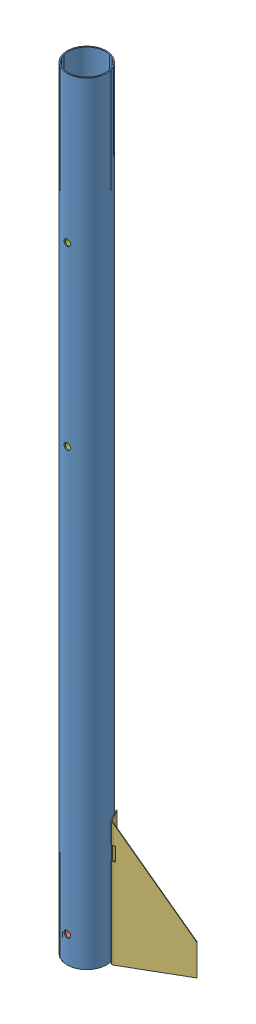
SolidWorks assembly rocket, configuration Default. Lengths in mm.
Overall size (97.97 500 47.6).
304 component instances, 53 part files, 30 mates.
Components (placement in the parent):
- pipe-1: pipe [Default] at (110.8047 11.7037 420.9903) size (25.5 500 25.5)
- nozle-2: nozle [Default] at (113.2966 34.1262 426.4615) x (0 -1 0) z (-0.414497 0 -0.91005) size (27 24 24)
- stabiliser-1: stabiliser [Default] at (90.1864 51.7037 433.7403) x (-1 0 0) z (0 -1 0) size (10 40.92 80) (hidden)
- pan head cross collar screw_din-2: pan head cross collar screw_din [DIN 967 - M4 x 5 - Z --- 3.6C] at (110.8047 29.0148 437.2903) x (0 0 -1) z (-0.790424 0.61256 0) size (7.93 10 10) (hidden)
- stabiliser-2: stabiliser [Default] at (132.1556 51.7037 432.4712) x (0.5 0 0.866025) z (0 -1 0) size (10 40.92 80)
- stabiliser-3: stabiliser [Default] at (110.072 51.7037 396.7593) x (0.5 0 -0.866025) z (0 -1 0) size (10 40.92 80)
- pan head cross collar screw_din-5: pan head cross collar screw_din [DIN 967 - M4 x 5 - Z --- 3.6C] at (124.9209 29.0148 412.8403) x (-0.866025 0 0.5) z (0.395212 0.61256 0.684527) size (7.93 10 10)
- pan head cross collar screw_din-6: pan head cross collar screw_din [DIN 967 - M4 x 5 - Z --- 3.6C] at (96.6885 29.0148 412.8403) x (0.866025 0 0.5) z (0.395212 0.61256 -0.684527) size (7.93 10 10)
- fuel with shielding and channel-1: fuel with shielding and channel [Default] at (110.8047 38.7037 420.9903) x (-0.053752 0 -0.998554) z (0.998554 0 -0.053752) size (24 85 24)
  - fuel-1: fuel [Default] at origin size (22 85 22)
  - fuel shielding-1: fuel shielding [Default] at origin size (24 85 24)
- fuel with shielding and channel-2: fuel with shielding and channel [Default] at (110.8047 123.7037 420.9903) x (-0.053752 0 -0.998554) z (0.998554 0 -0.053752) size (24 85 24)
  - fuel-1: fuel [Default] at origin size (22 85 22)
  - fuel shielding-1: fuel shielding [Default] at origin size (24 85 24)
- fuel with shielding-1: fuel with shielding [Default] at (110.8047 208.7037 420.9903) size (24 85 24)
  - fuel-1: fuel [Default] at origin size (22 85 22)
  - fuel shielding-1: fuel shielding [Default] at origin size (24 85 24)
- cap-1: cap [Default] at (112.1429 290.3844 427.2426) x (0 -1 0) z (0.209294 0 0.977853) size (18 24 24)
- o ring-3: o ring [Default] at (110.8047 24.4537 420.9903) size (24 1.5 24)
- o ring-4: o ring [Default] at (110.8047 33.9537 420.9903) size (24 1.5 24)
- o ring-5: o ring [Default] at (110.8047 24.4537 420.9903) size (24 1.5 24)
- o ring-7: o ring [Default] at (110.8047 307.4537 420.9903) x (0.994876 0 -0.101103) z (0.101103 0 0.994876) size (24 1.5 24)
- o ring-8: o ring [Default] at (110.8047 297.9537 420.9903) x (0.994876 0 -0.101103) z (0.101103 0 0.994876) size (24 1.5 24)
- electronics module-1: electronics module [Default] at (184.9767 308.3029 400.1739) x (0 0 1) z (-1 0 0) size (21.83 94.3 23.62)
  - PCB-1: PCB [Default] at (20.7064 167.5504 -10.283) x (0 -1 0) z (-1 0 0) size (88.26 23.62 14)
    - R05-1: R05 [Default] at origin size (0.95 1.7 0.6)
      - 959206216-1: 959206216 [Default] at (123.9521 73.9609 0) size (0.95 0.27 0.6)
        - Extruded-1: Extruded [Default] at origin size (0.95 0.27 0.6)
      - 959206352-1: 959206352 [Default] at (123.9521 74.6759 0) size (0.95 1.16 0.6)
        - Extruded-1-1: Extruded-1 [Default] at origin size (0.95 1.16 0.6)
      - 959206216-2: 959206216 [Default] at (123.9521 75.3909 0) size (0.95 0.27 0.6)
        - Extruded-1: Extruded [Default] at origin size (0.95 0.27 0.6)
    - R04-1: R04 [Default] at origin size (0.95 1.7 0.6)
      - 959206216-1: 959206216 [Default] at (141.478 81.581 0) size (0.95 0.27 0.6)
        - Extruded-1: Extruded [Default] at origin size (0.95 0.27 0.6)
      - 959206352-1: 959206352 [Default] at (141.478 82.296 0) size (0.95 1.16 0.6)
        - Extruded-1-1: Extruded-1 [Default] at origin size (0.95 1.16 0.6)
      - 959206216-2: 959206216 [Default] at (141.478 83.011 0) size (0.95 0.27 0.6)
        - Extruded-1: Extruded [Default] at origin size (0.95 0.27 0.6)
    - R03-1: R03 [Default] at origin size (3.35 1.75 0.75)
      - 959206760-1: 959206760 [Default] at (147.8506 77.6516 0) size (0.49 1.75 0.75)
        - Extruded-2-1: Extruded-2 [Default] at origin size (0.49 1.75 0.75)
      - 959206896-1: 959206896 [Default] at (149.2781 77.6516 0) size (2.36 1.75 0.75)
        - Extruded-3-1: Extruded-3 [Default] at origin size (2.36 1.75 0.75)
      - 959206760-2: 959206760 [Default] at (150.7056 77.6516 0) size (0.49 1.75 0.75)
        - Extruded-2-1: Extruded-2 [Default] at origin size (0.49 1.75 0.75)
    - R02-1: R02 [Default] at origin size (1.75 3.35 0.75)
      - 959207032-1: 959207032 [Default] at (128.1431 81.3844 0) size (1.75 0.49 0.75)
        - Extruded-4-1: Extruded-4 [Default] at origin size (1.75 0.49 0.75)
      - 959207168-1: 959207168 [Default] at (128.1431 79.9569 0) size (1.75 2.36 0.75)
        - Extruded-5-1: Extruded-5 [Default] at origin size (1.75 2.36 0.75)
      - 959207032-2: 959207032 [Default] at (128.1431 78.5294 0) size (1.75 0.49 0.75)
        - Extruded-4-1: Extruded-4 [Default] at origin size (1.75 0.49 0.75)
    - R01-1: R01 [Default] at origin size (3.35 1.75 0.75)
      - 959206760-1: 959206760 [Default] at (117.3285 91.9479 0) size (0.49 1.75 0.75)
        - Extruded-2-1: Extruded-2 [Default] at origin size (0.49 1.75 0.75)
      - 959206896-1: 959206896 [Default] at (115.901 91.9479 0) size (2.36 1.75 0.75)
        - Extruded-3-1: Extruded-3 [Default] at origin size (2.36 1.75 0.75)
      - 959206760-2: 959206760 [Default] at (114.4735 91.9479 0) size (0.49 1.75 0.75)
        - Extruded-2-1: Extruded-2 [Default] at origin size (0.49 1.75 0.75)
    - U3-1: U3 [Default] at origin size (43.25 15.95 5.5)
      - 959206080-1: 959206080 [Default] at (102.177 84.441 -2.3912) size (43.25 15.95 2)
        - Extruded-6-1: Extruded-6 [Default] at origin size (43.25 15.95 2)
      - 959205944-1: 959205944 [Default] at (85.217 88.291 -2.8912) size (0.4 0.4 5.5)
        - Extruded-7-1: Extruded-7 [Default] at origin size (0.4 0.4 5.5)
      - 959205944-2: 959205944 [Default] at (85.217 85.751 -2.8912) size (0.4 0.4 5.5)
        - Extruded-7-1: Extruded-7 [Default] at origin size (0.4 0.4 5.5)
      - 959205944-3: 959205944 [Default] at (82.677 88.291 -2.8912) size (0.4 0.4 5.5)
        - Extruded-7-1: Extruded-7 [Default] at origin size (0.4 0.4 5.5)
      - 959205944-4: 959205944 [Default] at (82.677 85.751 -2.8912) size (0.4 0.4 5.5)
        - Extruded-7-1: Extruded-7 [Default] at origin size (0.4 0.4 5.5)
      - 959205944-5: 959205944 [Default] at (85.217 83.211 -2.8912) size (0.4 0.4 5.5)
        - Extruded-7-1: Extruded-7 [Default] at origin size (0.4 0.4 5.5)
      - 959205944-6: 959205944 [Default] at (85.217 80.671 -2.8912) size (0.4 0.4 5.5)
        - Extruded-7-1: Extruded-7 [Default] at origin size (0.4 0.4 5.5)
      - 959205944-7: 959205944 [Default] at (82.677 83.211 -2.8912) size (0.4 0.4 5.5)
        - Extruded-7-1: Extruded-7 [Default] at origin size (0.4 0.4 5.5)
      - 959205944-8: 959205944 [Default] at (82.677 80.671 -2.8912) size (0.4 0.4 5.5)
        - Extruded-7-1: Extruded-7 [Default] at origin size (0.4 0.4 5.5)
    - R11-1: R11 [Default] at origin size (1.35 2.2 0.7)
      - 959207304-1: 959207304 [Default] at (133.9849 94.0691 0) size (1.35 0.42 0.7)
        - Extruded-8-1: Extruded-8 [Default] at origin size (1.35 0.42 0.7)
      - 959207440-1: 959207440 [Default] at (133.9849 93.1791 0) size (1.35 1.36 0.7)
        - Extruded-9-1: Extruded-9 [Default] at origin size (1.35 1.36 0.7)
      - 959207304-2: 959207304 [Default] at (133.9849 92.2891 0) size (1.35 0.42 0.7)
        - Extruded-8-1: Extruded-8 [Default] at origin size (1.35 0.42 0.7)
    - Q3-1: Q3 [Default] at origin size (1.4 3 1)
      - 959206624-1: 959206624 [Default] at (105.664 90.805 0.1) size (1.4 3 1)
        - Extruded-10-1: Extruded-10 [Default] at origin size (1.4 3 1)
    - P6-1: P6 [Default] at origin size (16.31 15.21 2.47)
      - User Library-Micro SD-1: User Library-Micro SD [Default] at (103.6713 76.9862 0.04) x (-1 0 0) z (0 0 1) size (16.31 15.21 2.47)
    - Q1-1: Q1 [Default] at origin size (3 1.4 1)
      - 959206488-1: 959206488 [Default] at (75.057 92.3634 0.1) size (3 1.4 1)
        - Extruded-11-1: Extruded-11 [Default] at origin size (3 1.4 1)
    - C1-1: C1 [Default] at origin size (3.4 1.8 1.9)
      - 959208392-1: 959208392 [Default] at (133.022 83.687 0) size (0.5 1.8 1.9)
        - Extruded-12-1: Extruded-12 [Default] at origin size (0.5 1.8 1.9)
      - 959208392-2: 959208392 [Default] at (130.122 83.687 0) size (0.5 1.8 1.9)
        - Extruded-12-1: Extruded-12 [Default] at origin size (0.5 1.8 1.9)
      - 959208256-1: 959208256 [Default] at (131.572 83.687 0) size (2.4 1.8 1.9)
        - Extruded-13-1: Extruded-13 [Default] at origin size (2.4 1.8 1.9)
    - C2-1: C2 [Default] at origin size (0.95 1.75 1)
      - 959208664-1: 959208664 [Default] at (140.8925 85.698 0) size (0.95 0.35 1)
        - Extruded-14-1: Extruded-14 [Default] at origin size (0.95 0.35 1)
      - 959208664-2: 959208664 [Default] at (140.8925 87.098 0) size (0.95 0.35 1)
        - Extruded-14-1: Extruded-14 [Default] at origin size (0.95 0.35 1)
      - 959208528-1: 959208528 [Default] at (140.8925 86.398 0) size (0.95 1.05 1)
        - Extruded-15-1: Extruded-15 [Default] at origin size (0.95 1.05 1)
    - C3-1: C3 [Default] at origin size (0.95 1.75 1)
      - 959208664-1: 959208664 [Default] at (146.558 83.0961 0) size (0.95 0.35 1)
        - Extruded-14-1: Extruded-14 [Default] at origin size (0.95 0.35 1)
      - 959208664-2: 959208664 [Default] at (146.558 84.4961 0) size (0.95 0.35 1)
        - Extruded-14-1: Extruded-14 [Default] at origin size (0.95 0.35 1)
      - 959208528-1: 959208528 [Default] at (146.558 83.7961 0) size (0.95 1.05 1)
        - Extruded-15-1: Extruded-15 [Default] at origin size (0.95 1.05 1)
    - C5-1: C5 [Default] at origin size (1.75 0.95 1)
      - 959208936-1: 959208936 [Default] at (142.772 80.518 0) size (0.35 0.95 1)
        - Extruded-16-1: Extruded-16 [Default] at origin size (0.35 0.95 1)
      - 959208936-2: 959208936 [Default] at (144.172 80.518 0) size (0.35 0.95 1)
        - Extruded-16-1: Extruded-16 [Default] at origin size (0.35 0.95 1)
      - 959208800-1: 959208800 [Default] at (143.472 80.518 0) size (1.05 0.95 1)
        - Extruded-17-1: Extruded-17 [Default] at origin size (1.05 0.95 1)
    - C6-1: C6 [Default] at origin size (1.75 0.95 1)
      - 959208800-1: 959208800 [Default] at (135.5285 81.379 0) size (1.05 0.95 1)
        - Extruded-17-1: Extruded-17 [Default] at origin size (1.05 0.95 1)
      - 959208936-1: 959208936 [Default] at (136.2285 81.379 0) size (0.35 0.95 1)
        - Extruded-16-1: Extruded-16 [Default] at origin size (0.35 0.95 1)
      - 959208936-2: 959208936 [Default] at (134.8286 81.379 0) size (0.35 0.95 1)
        - Extruded-16-1: Extruded-16 [Default] at origin size (0.35 0.95 1)
    - C7-1: C7 [Default] at origin size (0.95 1.75 1)
      - 959208528-1: 959208528 [Default] at (145.288 83.8282 0) size (0.95 1.05 1)
        - Extruded-15-1: Extruded-15 [Default] at origin size (0.95 1.05 1)
      - 959208664-1: 959208664 [Default] at (145.288 83.1282 0) size (0.95 0.35 1)
        - Extruded-14-1: Extruded-14 [Default] at origin size (0.95 0.35 1)
      - 959208664-2: 959208664 [Default] at (145.288 84.5282 0) size (0.95 0.35 1)
        - Extruded-14-1: Extruded-14 [Default] at origin size (0.95 0.35 1)
    - C8-1: C8 [Default] at origin size (1.45 2.2 1)
      - 959207984-1: 959207984 [Default] at (115.697 77.2073 0) size (1.45 1.2 1)
        - Extruded-18-1: Extruded-18 [Default] at origin size (1.45 1.2 1)
      - 959207848-1: 959207848 [Default] at (115.697 78.0573 0) size (1.45 0.5 1)
        - Extruded-19-1: Extruded-19 [Default] at origin size (1.45 0.5 1)
      - 959207848-2: 959207848 [Default] at (115.697 76.3573 0) size (1.45 0.5 1)
        - Extruded-19-1: Extruded-19 [Default] at origin size (1.45 0.5 1)
    - C9-1: C9 [Default] at origin size (0.95 1.75 1)
      - 959208528-1: 959208528 [Default] at (108.577 76.835 0) size (0.95 1.05 1)
        - Extruded-15-1: Extruded-15 [Default] at origin size (0.95 1.05 1)
      - 959208664-1: 959208664 [Default] at (108.577 76.135 0) size (0.95 0.35 1)
        - Extruded-14-1: Extruded-14 [Default] at origin size (0.95 0.35 1)
      - 959208664-2: 959208664 [Default] at (108.577 77.535 0) size (0.95 0.35 1)
        - Extruded-14-1: Extruded-14 [Default] at origin size (0.95 0.35 1)
    - C10-1: C10 [Default] at origin size (0.95 1.75 1)
      - 959208664-1: 959208664 [Default] at (109.7632 77.5843 0) size (0.95 0.35 1)
        - Extruded-14-1: Extruded-14 [Default] at origin size (0.95 0.35 1)
      - 959208664-2: 959208664 [Default] at (109.7632 76.1843 0) size (0.95 0.35 1)
        - Extruded-14-1: Extruded-14 [Default] at origin size (0.95 0.35 1)
      - 959208528-1: 959208528 [Default] at (109.7632 76.8843 0) size (0.95 1.05 1)
        - Extruded-15-1: Extruded-15 [Default] at origin size (0.95 1.05 1)
    - C11-1: C11 [Default] at origin size (0.95 1.75 1)
      - 959208664-1: 959208664 [Default] at (122.4827 75.652 0) size (0.95 0.35 1)
        - Extruded-14-1: Extruded-14 [Default] at origin size (0.95 0.35 1)
      - 959208664-2: 959208664 [Default] at (122.4827 77.052 0) size (0.95 0.35 1)
        - Extruded-14-1: Extruded-14 [Default] at origin size (0.95 0.35 1)
      - 959208528-1: 959208528 [Default] at (122.4827 76.352 0) size (0.95 1.05 1)
        - Extruded-15-1: Extruded-15 [Default] at origin size (0.95 1.05 1)
    - C12-1: C12 [Default] at origin size (1.75 0.95 1)
      - 959208936-1: 959208936 [Default] at (92.521 76.327 0) size (0.35 0.95 1)
        - Extruded-16-1: Extruded-16 [Default] at origin size (0.35 0.95 1)
      - 959208936-2: 959208936 [Default] at (91.121 76.327 0) size (0.35 0.95 1)
        - Extruded-16-1: Extruded-16 [Default] at origin size (0.35 0.95 1)
      - 959208800-1: 959208800 [Default] at (91.821 76.327 0) size (1.05 0.95 1)
        - Extruded-17-1: Extruded-17 [Default] at origin size (1.05 0.95 1)
    - P1-1: P1 [Default] at origin size (7.4 5.75 10.4)
      - P1-subassembly-1-1: P1-subassembly-1 [Default] at (131.5051 81.6569 -0.3912) x (-1 0 0) z (0 -1 0) size (7.4 10.4 5.75)
        - User Library-JST B2B-XH-A-1: User Library-JST B2B-XH-A [Default] at origin size (0.64 3.4 0.64)
        - User Library-JST B2B-XH-A-1-1: User Library-JST B2B-XH-A-1 [Default] at origin size (0.64 3.4 0.64)
        - User Library-JST B2B-XH-A-2-1: User Library-JST B2B-XH-A-2 [Default] at origin size (0.64 4.5 0.64)
        - User Library-JST B2B-XH-A-3-1: User Library-JST B2B-XH-A-3 [Default] at origin size (0.64 4.5 0.64)
        - User Library-JST B2B-XH-A-4-1: User Library-JST B2B-XH-A-4 [Default] at origin size (7.4 7 5.75)
    - P3-1: P3 [Default] at origin size (12.4 5.75 10.4)
      - SW3dPS-jst-b4b-xh-a-1-1: SW3dPS-jst-b4b-xh-a-1 [Default] at (134.0049 88.1301 -0.3912) x (-1 0 0) z (0 -1 0) size (12.4 10.4 5.75)
    - P4-1: P4 [Default] at origin
      - connector-1: connector [Default] at (76.2639 56.9549 -0.3912) x (0 1 0) z (0 0 -1)
    - P5-1: P5 [Default] at origin
      - connector-1: connector [Default] at (157.0351 111.9551 -0.3912) x (0 -1 0) z (0 0 -1)
    - Q2-1: Q2 [Default] at origin size (1.4 3 1)
      - 959206624-1: 959206624 [Default] at (158.496 90.17 0.1) size (1.4 3 1)
        - Extruded-10-1: Extruded-10 [Default] at origin size (1.4 3 1)
    - R1-1: R1 [Default] at origin size (0.95 1.7 0.6)
      - 959206216-1: 959206216 [Default] at (142.6211 77.6287 0) size (0.95 0.27 0.6)
        - Extruded-1: Extruded [Default] at origin size (0.95 0.27 0.6)
      - 959206352-1: 959206352 [Default] at (142.6211 78.3437 0) size (0.95 1.16 0.6)
        - Extruded-1-1: Extruded-1 [Default] at origin size (0.95 1.16 0.6)
      - 959206216-2: 959206216 [Default] at (142.6211 79.0587 0) size (0.95 0.27 0.6)
        - Extruded-1: Extruded [Default] at origin size (0.95 0.27 0.6)
    - R2-1: R2 [Default] at origin size (1.4 2.15 0.7)
      - 959208120-1: 959208120 [Default] at (111.8912 75.852 0) size (1.4 2.15 0.7)
        - Extruded-20-1: Extruded-20 [Default] at origin size (1.4 2.15 0.7)
    - R3-1: R3 [Default] at origin size (1.35 2.2 0.7)
      - 959207304-1: 959207304 [Default] at (114.1729 78.1061 0) size (1.35 0.42 0.7)
        - Extruded-8-1: Extruded-8 [Default] at origin size (1.35 0.42 0.7)
      - 959207440-1: 959207440 [Default] at (114.1729 77.2161 0) size (1.35 1.36 0.7)
        - Extruded-9-1: Extruded-9 [Default] at origin size (1.35 1.36 0.7)
      - 959207304-2: 959207304 [Default] at (114.1729 76.3261 0) size (1.35 0.42 0.7)
        - Extruded-8-1: Extruded-8 [Default] at origin size (1.35 0.42 0.7)
    - R4-1: R4 [Default] at origin size (1.7 0.95 0.6)
      - 959209072-1: 959209072 [Default] at (119.5871 82.2961 0) size (0.27 0.95 0.6)
        - Extruded-21-1: Extruded-21 [Default] at origin size (0.27 0.95 0.6)
      - 959209208-1: 959209208 [Default] at (118.8721 82.2961 0) size (1.16 0.95 0.6)
        - Extruded-22-1: Extruded-22 [Default] at origin size (1.16 0.95 0.6)
      - 959209072-2: 959209072 [Default] at (118.1571 82.2961 0) size (0.27 0.95 0.6)
        - Extruded-21-1: Extruded-21 [Default] at origin size (0.27 0.95 0.6)
    - R5-1: R5 [Default] at origin size (0.95 1.7 0.6)
      - 959206216-1: 959206216 [Default] at (120.9041 81.6699 0) size (0.95 0.27 0.6)
        - Extruded-1: Extruded [Default] at origin size (0.95 0.27 0.6)
      - 959206352-1: 959206352 [Default] at (120.9041 82.3849 0) size (0.95 1.16 0.6)
        - Extruded-1-1: Extruded-1 [Default] at origin size (0.95 1.16 0.6)
      - 959206216-2: 959206216 [Default] at (120.9041 83.0999 0) size (0.95 0.27 0.6)
        - Extruded-1: Extruded [Default] at origin size (0.95 0.27 0.6)
    - R6-1: R6 [Default] at origin size (1.4 2.15 0.7)
      - 959208120-1: 959208120 [Default] at (122.9827 82.385 0) size (1.4 2.15 0.7)
        - Extruded-20-1: Extruded-20 [Default] at origin size (1.4 2.15 0.7)
    - R8-1: R8 [Default] at origin size (2.51 2.51 0.7)
      - 959207576-1: 959207576 [Default] at (78.6187 92.1936 0) size (1.25 1.25 0.7)
        - Extruded-23-1: Extruded-23 [Default] at origin size (1.25 1.25 0.7)
      - 959207712-1: 959207712 [Default] at (79.248 92.8229 0) size (1.92 1.92 0.7)
        - Extruded-24-1: Extruded-24 [Default] at origin size (1.92 1.92 0.7)
      - 959207576-2: 959207576 [Default] at (79.8773 93.4522 0) size (1.25 1.25 0.7)
        - Extruded-23-1: Extruded-23 [Default] at origin size (1.25 1.25 0.7)
    - R13-1: R13 [Default] at origin size (2.2 1.35 0.7)
      - 959209344-1: 959209344 [Default] at (105.4089 93.8529 0) size (0.42 1.35 0.7)
        - Extruded-25-1: Extruded-25 [Default] at origin size (0.42 1.35 0.7)
      - 959209480-1: 959209480 [Default] at (106.2989 93.8529 0) size (1.36 1.35 0.7)
        - Extruded-26-1: Extruded-26 [Default] at origin size (1.36 1.35 0.7)
      - 959209344-2: 959209344 [Default] at (107.1889 93.8529 0) size (0.42 1.35 0.7)
        - Extruded-25-1: Extruded-25 [Default] at origin size (0.42 1.35 0.7)
    - R7-1: R7 [Default] at origin size (2.2 1.35 0.7)
      - 959209344-1: 959209344 [Default] at (76.5821 79.5961 0) size (0.42 1.35 0.7)
        - Extruded-25-1: Extruded-25 [Default] at origin size (0.42 1.35 0.7)
      - 959209480-1: 959209480 [Default] at (75.6921 79.5961 0) size (1.36 1.35 0.7)
        - Extruded-26-1: Extruded-26 [Default] at origin size (1.36 1.35 0.7)
      - 959209344-2: 959209344 [Default] at (74.8021 79.5961 0) size (0.42 1.35 0.7)
        - Extruded-25-1: Extruded-25 [Default] at origin size (0.42 1.35 0.7)
    - R9-1: R9 [Default] at origin size (1.35 2.2 0.7)
      - 959207304-1: 959207304 [Default] at (77.5971 95.5049 0) size (1.35 0.42 0.7)
        - Extruded-8-1: Extruded-8 [Default] at origin size (1.35 0.42 0.7)
      - 959207440-1: 959207440 [Default] at (77.5971 94.6149 0) size (1.35 1.36 0.7)
        - Extruded-9-1: Extruded-9 [Default] at origin size (1.35 1.36 0.7)
      - 959207304-2: 959207304 [Default] at (77.5971 93.7249 0) size (1.35 0.42 0.7)
        - Extruded-8-1: Extruded-8 [Default] at origin size (1.35 0.42 0.7)
    - R14-1: R14 [Default] at origin size (1.35 2.2 0.7)
      - 959207304-1: 959207304 [Default] at (110.6132 93.495 0) size (1.35 0.42 0.7)
        - Extruded-8-1: Extruded-8 [Default] at origin size (1.35 0.42 0.7)
      - 959207440-1: 959207440 [Default] at (110.6132 92.605 0) size (1.35 1.36 0.7)
        - Extruded-9-1: Extruded-9 [Default] at origin size (1.35 1.36 0.7)
      - 959207304-2: 959207304 [Default] at (110.6132 91.715 0) size (1.35 0.42 0.7)
        - Extruded-8-1: Extruded-8 [Default] at origin size (1.35 0.42 0.7)
    - R10-1: R10 [Default] at origin size (3.35 1.75 0.75)
      - 959206760-1: 959206760 [Default] at (152.7506 83.5661 0) size (0.49 1.75 0.75)
        - Extruded-2-1: Extruded-2 [Default] at origin size (0.49 1.75 0.75)
      - 959206896-1: 959206896 [Default] at (154.1781 83.5661 0) size (2.36 1.75 0.75)
        - Extruded-3-1: Extruded-3 [Default] at origin size (2.36 1.75 0.75)
      - 959206760-2: 959206760 [Default] at (155.6056 83.5661 0) size (0.49 1.75 0.75)
        - Extruded-2-1: Extruded-2 [Default] at origin size (0.49 1.75 0.75)
    - R12-1: R12 [Default] at origin size (1.35 2.2 0.7)
      - 959207304-1: 959207304 [Default] at (152.7811 87.2879 0) size (1.35 0.42 0.7)
        - Extruded-8-1: Extruded-8 [Default] at origin size (1.35 0.42 0.7)
      - 959207440-1: 959207440 [Default] at (152.7811 86.3979 0) size (1.35 1.36 0.7)
        - Extruded-9-1: Extruded-9 [Default] at origin size (1.35 1.36 0.7)
      - 959207304-2: 959207304 [Default] at (152.7811 85.5079 0) size (1.35 0.42 0.7)
        - Extruded-8-1: Extruded-8 [Default] at origin size (1.35 0.42 0.7)
    - U1-1: U1 [Default] at origin size (1.75 3 1.45)
      - 959209616-1: 959209616 [Default] at (137.668 84.449 0) size (1.75 3 1.45)
        - Extruded-27-1: Extruded-27 [Default] at origin size (1.75 3 1.45)
    - U4-1: U4 [Default] at origin size (7 7 1.2)
      - 959209752-1: 959209752 [Default] at (110.9632 83.702 0) size (7 7 1.2)
        - Extruded-28-1: Extruded-28 [Default] at origin size (7 7 1.2)
    - BUZ1-1: BUZ1 [Default] at origin size (12 12 14)
      - SW3dPS-WST-1203UX-1: SW3dPS-WST-1203UX [Default] at (146.685 84.5049 -0.4912) x (0 -1 0) z (1 0 0) size (12 14 12)
    - C4-1: C4 [Default] at origin size (0.95 1.75 1)
      - 959208528-1: 959208528 [Default] at (127.791 83.885 0) size (0.95 1.05 1)
        - Extruded-15-1: Extruded-15 [Default] at origin size (0.95 1.05 1)
      - 959208664-1: 959208664 [Default] at (127.791 83.185 0) size (0.95 0.35 1)
        - Extruded-14-1: Extruded-14 [Default] at origin size (0.95 0.35 1)
      - 959208664-2: 959208664 [Default] at (127.791 84.585 0) size (0.95 0.35 1)
        - Extruded-14-1: Extruded-14 [Default] at origin size (0.95 0.35 1)
    - D1-1: D1 [Default] at origin size (1.45 2.2 1.4)
      - 959209888-1: 959209888 [Default] at (77.089 89.876 0) size (1.45 2.2 1.4)
        - Extruded-29-1: Extruded-29 [Default] at origin size (1.45 2.2 1.4)
    - D2-1: D2 [Default] at origin size (2.2 1.45 1.4)
      - 959210024-1: 959210024 [Default] at (155.107 90.769 0) size (2.2 1.45 1.4)
        - Extruded-30-1: Extruded-30 [Default] at origin size (2.2 1.45 1.4)
    - D3-1: D3 [Default] at origin size (1.45 2.2 1.4)
      - 959209888-1: 959209888 [Default] at (108.585 90.769 0) size (1.45 2.2 1.4)
        - Extruded-29-1: Extruded-29 [Default] at origin size (1.45 2.2 1.4)
    - Board-1: Board [Default] at origin size (88.26 23.62 0.39)
  - cross recessed binding head screw_jis-1: cross recessed binding head screw_jis [JIS B 1111 Binding head screw M2 x 6 --6S] at (22.2976 10.6684 65.893) x (-1 0 0) z (0 -0.924225 -0.381849) size (7.17 4.3 4.3) (hidden)
  - cross recessed binding head screw_jis-4: cross recessed binding head screw_jis [JIS B 1111 Binding head screw M2 x 6 --6S] at (22.2976 90.9084 64.617) x (-1 0 0) z (0 -0.85199 -0.523557) size (7.17 4.3 4.3) (hidden)
  - cross recessed binding head screw_jis-5: cross recessed binding head screw_jis [JIS B 1111 Binding head screw M2 x 6 --6S] at (22.2976 25.3225 82.261) x (-1 0 0) z (0 -0.77839 -0.627782) size (7.17 4.3 4.3) (hidden)
  - electronics holder-2: electronics holder [Default] at (20.8164 4.4009 74.172) size (9.95 94.3 23.56)
  - camera-1: camera [Default] at (15.3664 565.0334 -207.5796) x (0 1 0) z (0 0 -1) size (54 11.5 19.4)
  - LED 3W-1: LED 3W [Default] at (14.0164 25.4867 74.172) x (0 1 0) z (0 0 1) size (14.67 5.4 8)
- cap-2: cap [Default] at (117.1983 404.6844 420.9314) x (0 -1 0) z (0.999958 0 -0.0092) size (18 24 24)
- o ring-9: o ring [Default] at (110.8047 421.7537 420.9903) x (0.100208 0 -0.994967) z (0.994967 0 0.100208) size (24 1.5 24)
- o ring-11: o ring [Default] at (110.8047 412.2537 420.9903) x (-0.089094 0 -0.996023) z (0.996023 0 -0.089094) size (24 1.5 24)
Mates (geometry in assembly coordinates):
- Concentric1: concentric: circle of pipe-1; circle of nozle-2
- Coincident1: coincident: circle of pipe-1; circle of nozle-2
- Coincident2: coincident: plane of pipe-1 through (110.8047 11.7037 420.9903) normal (0 -1 0); plane of stabiliser-1 through (115.1864 11.7037 434.2403) normal (0 -1 0)
- Tangent1: tangent: cylinder of pipe-1 through (110.8047 511.7037 420.9903) axis (0 -1 0) radius 12.75; plane of stabiliser-1 through (90.1864 51.7037 433.7403) normal (0 0 -1)
- Coincident5: coincident: circle of pipe-1; point of stabiliser-1
- Parallel1: parallel: plane of stabiliser-1 through (105.6864 51.7037 449.6637) normal (1 0 0); plane of assembly through (0 0 0) normal (1 0 0)
- Coincident9: coincident: plane of pan head cross collar screw_din-2 through (109.5796 27.4339 434.2403) normal (0 0 -1); plane of stabiliser-1 through (90.1864 51.7037 434.2403) normal (0 0 1)
- Concentric8: concentric: circle of stabiliser-1; circle of pan head cross collar screw_din-2
- Concentric9: concentric: cylinder of pipe-1 through (110.8047 511.7037 420.9903) axis (0 -1 0) radius 12; cylinder of fuel with shielding and channel-1/fuel shielding-1 through (110.8047 123.7037 420.9903) axis (0 -1 0) radius 12
- Coincident14: coincident: circle of nozle-2; circle of fuel with shielding and channel-1/fuel shielding-1
- Concentric10: concentric: cylinder of pipe-1 through (110.8047 511.7037 420.9903) axis (0 -1 0) radius 12; cylinder of ? through (110.8047 293.7037 420.9903) axis (0 -1 0) radius 12
- Coincident15: coincident: plane of fuel with shielding and channel-2/fuel-1 through (110.8047 208.7037 420.9903) normal (0 1 0); plane of ? through (110.8047 208.7037 420.9903) normal (0 -1 0)
- Concentric11: concentric: cylinder of pipe-1 through (110.8047 511.7037 420.9903) axis (0 -1 0) radius 12; cylinder of cap-1 through (110.8047 311.7037 420.9903) axis (0 1 0) radius 12
- Coincident16: coincident: plane of ? through (110.8047 293.7037 420.9903) normal (0 1 0); plane of cap-1 through (110.8047 293.7037 420.9903) normal (0 -1 0)
- Lock2: lock: unknown of nozle-2; unknown of ?
- Concentric13: concentric: cylinder of pipe-1 through (110.8047 511.7037 420.9903) axis (0 -1 0) radius 12; circle of o ring-3
- ProfileCenter1: profile center = 1.25 mm: circle of o ring-3; plane of nozle-2 through (115.1569 23.2037 430.5458) normal (0 1 0)
- Concentric17: concentric: cylinder of cap-1 through (110.8047 311.7037 420.9903) axis (0 1 0) radius 10.5; circle of o ring-7
- ProfileCenter2: profile center = 1.25 mm: circle of o ring-7; plane of cap-1 through (113.0023 306.2037 431.2577) normal (0 1 0)
- Concentric18: concentric aligned: cylinder of pipe-1 through (110.8047 511.7037 420.9903) axis (0 -1 0) radius 12; cylinder of ? through (110.8047 401.7037 420.9903) axis (0 -1 0) radius 11.95
- Coincident19: coincident anti-aligned: plane of cap-1 through (110.8047 311.7037 420.9903) normal (0 1 0); plane of ? through (110.8047 311.7037 420.9903) normal (0 -1 0)
- Concentric19: concentric: cylinder of pipe-1 through (110.8047 511.7037 420.9903) axis (0 -1 0) radius 12; cylinder of electronics module-1/electronics holder-2 through (110.8047 405.7037 420.9903) axis (0 -1 0) radius 11.95
- Parallel2: parallel: plane of pan head cross collar screw_din-2 through (107.7419 25.0626 435.2403) normal (0 0 1); plane of electronics module-1/electronics holder-2 through (99.0232 405.7037 418.9903) normal (0 0 1)
- Concentric20: concentric: cylinder of cap-2 through (110.8047 426.0037 420.9903) axis (0 1 0) radius 10.5; circle of o ring-9
- ProfileCenter3: profile center = 1.25 mm: circle of o ring-9; plane of cap-2 through (121.3042 420.5037 420.8937) normal (0 1 0)
- Concentric21: concentric: cylinder of pipe-1 through (110.8047 511.7037 420.9903) axis (0 -1 0) radius 12; cylinder of cap-2 through (110.8047 426.0037 420.9903) axis (0 1 0) radius 12
- Concentric24: concentric: cylinder of cap-2 through (110.8047 426.0037 420.9903) axis (0 1 0) radius 10.5; circle of o ring-11
- ProfileCenter5: profile center = 1.25 mm: circle of o ring-11; plane of cap-2 through (121.3042 411.0037 420.8937) normal (0 1 0)
- Distance1: distance = 1 mm: plane of electronics module-1/electronics holder-2 through (110.8047 312.7037 420.9903) normal (0 -1 0); plane of cap-1 through (110.8047 311.7037 420.9903) normal (0 1 0)
- Distance2: distance = 1 mm: plane of electronics module-1/electronics holder-2 through (110.8047 407.0037 420.9903) normal (0 1 0); plane of cap-2 through (110.8047 408.0037 420.9903) normal (0 -1 0)
